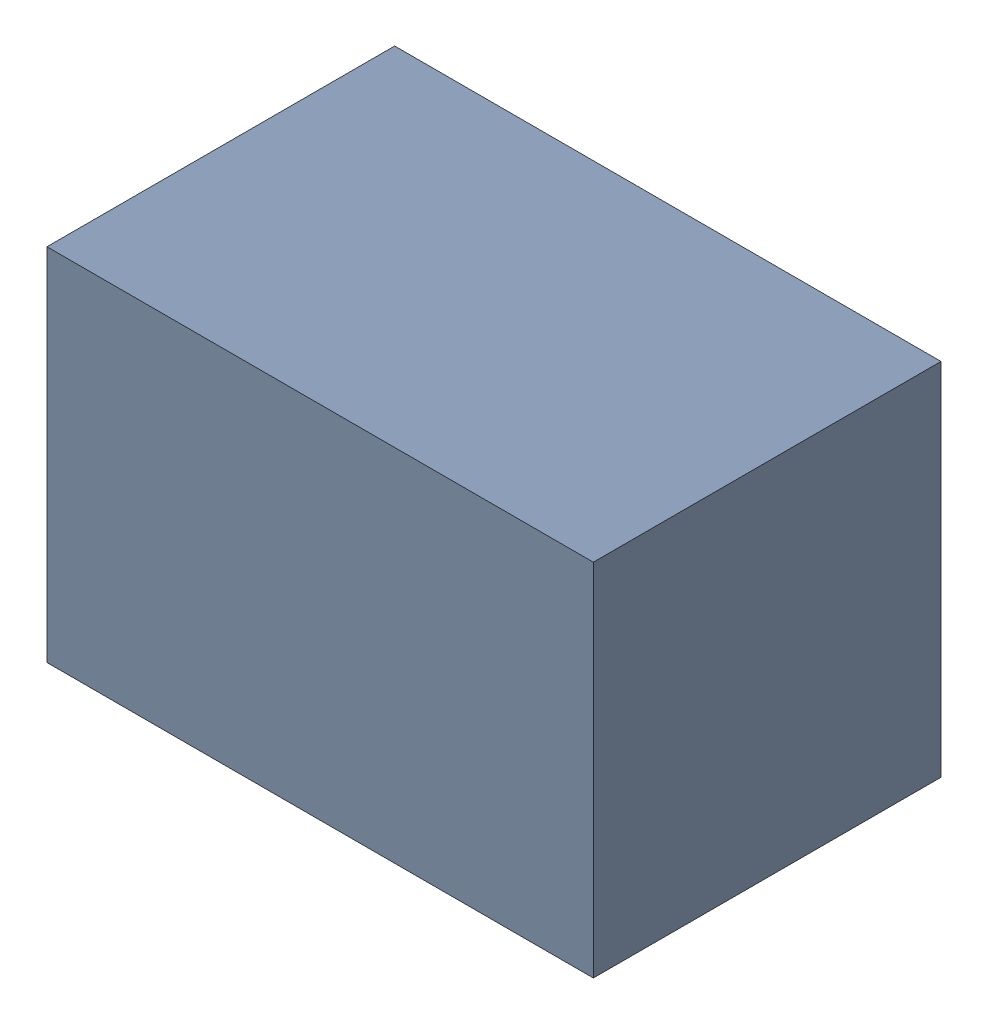
SolidWorks assembly C26, configuration Default. Lengths in mm.
Overall size (2.2 1.45 1.4).
2 component instances, 1 part files, 0 mates.
Components (placement in the parent):
- 1017092848-1: 1017092848 [Default] at (157.48 144.78 0) size (2.2 1.45 1.4)
  - Extruded_3-1: Extruded_3 [Default] at origin size (2.2 1.45 1.4)
